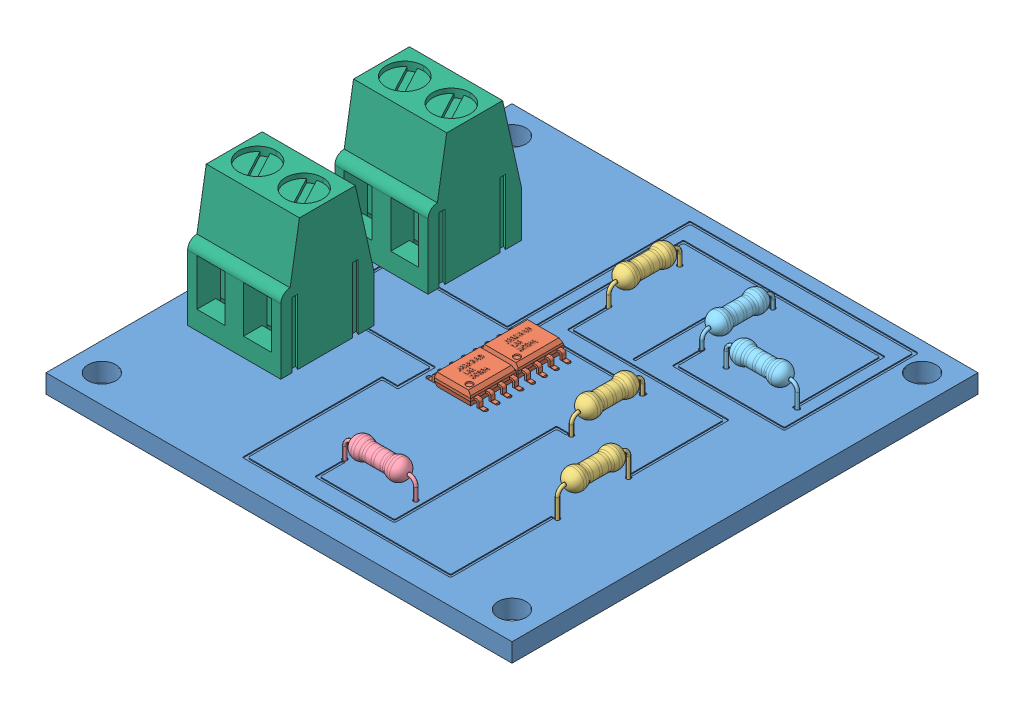
SolidWorks assembly PCB, configuration Predeterminado. Lengths in mm.
Overall size (50 21.09 50).
11 component instances, 6 part files, 14 mates.
Components (placement in the parent):
- Base PCB-1: Base PCB [Predeterminado] at (22.1257 1.9149 50) size (50 2 50)
- LM308M OPERATIONAL AMPLIFIER-2: LM308M OPERATIONAL AMPLIFIER [Default] at (-13.8014 3.7349 49.8133) x (0 0 -1) z (0 1 0) size (4.9 6 1.55)
- LM308M OPERATIONAL AMPLIFIER-3: LM308M OPERATIONAL AMPLIFIER [Default] at (-13.8014 3.7349 54.9133) x (0 0 -1) z (0 1 0) size (4.9 6 1.55)
- 10KR-1: 10KR [Default] at (3.1257 6.7115 57.3048) x (0 0 1) z (-1 0 0) size (7.97 9.8 2.2)
- 1KR-1: 1KR [Default] at (-9.9923 5.9416 67) size (7.97 9.8 2.2)
- 10KR-2: 10KR [Default] at (-3.8743 5.7208 48.81) x (0 0 1) z (-1 0 0) size (7.97 9.8 2.2)
- 10KR-3: 10KR [Default] at (-13.8743 5.8043 34.81) x (0 0 -1) z (1 0 0) size (7.97 9.8 2.2)
- 2KR-1: 2KR [Default] at (1.9357 6.2506 38) size (7.97 9.8 2.2)
- 2KR-2: 2KR [Default] at (-4.8743 5.5205 33.81) x (0 0 -1) z (1 0 0) size (7.97 9.8 2.2)
- KRE_2-1: KRE_2 [Valor predeterminado] at (0.9939 -15.7812 42.2341) x (1 0 0.000521) z (-0.000521 0 1) size (11.5 18.25 10.01)
- KRE_2-2: KRE_2 [Valor predeterminado] at (0.9939 -15.7812 58.0341) x (1 0 0.000521) z (-0.000521 0 1) size (11.5 18.25 10.01)
Mates (geometry in assembly coordinates):
- Coincidente2: coincident anti-aligned: plane of Base PCB-1 through (22.1257 3.9149 50) normal (0 1 0); plane of LM308M OPERATIONAL AMPLIFIER-2 through (-15.7514 3.9149 49.1783) normal (0 -1 0)
- Concéntrica1: concentric anti-aligned: circle of Base PCB-1; circle of 10KR-1
- Concéntrica2: concentric aligned: circle of Base PCB-1; circle of 10KR-1
- Concéntrica5: concentric: circle of Base PCB-1; circle of 10KR-2
- Concéntrica6: concentric anti-aligned: circle of Base PCB-1; circle of 10KR-2
- Concéntrica7: concentric aligned: circle of Base PCB-1; circle of 10KR-3
- Concéntrica8: concentric anti-aligned: circle of Base PCB-1; circle of 10KR-3
- Concéntrica9: concentric: circle of Base PCB-1; circle of 2KR-1
- Concéntrica10: concentric anti-aligned: circle of Base PCB-1; circle of 2KR-1
- Concéntrica11: concentric: circle of Base PCB-1; circle of 2KR-2
- Concéntrica12: concentric aligned: circle of Base PCB-1; circle of 2KR-2
- Tangente1: tangent anti-aligned: plane of Base PCB-1 through (22.1257 3.9149 50) normal (0 1 0); face of KRE_2-1
- Concéntrica14: concentric: circle of Base PCB-1; circle of 1KR-1
- Concéntrica15: concentric aligned: circle of Base PCB-1; circle of 1KR-1
